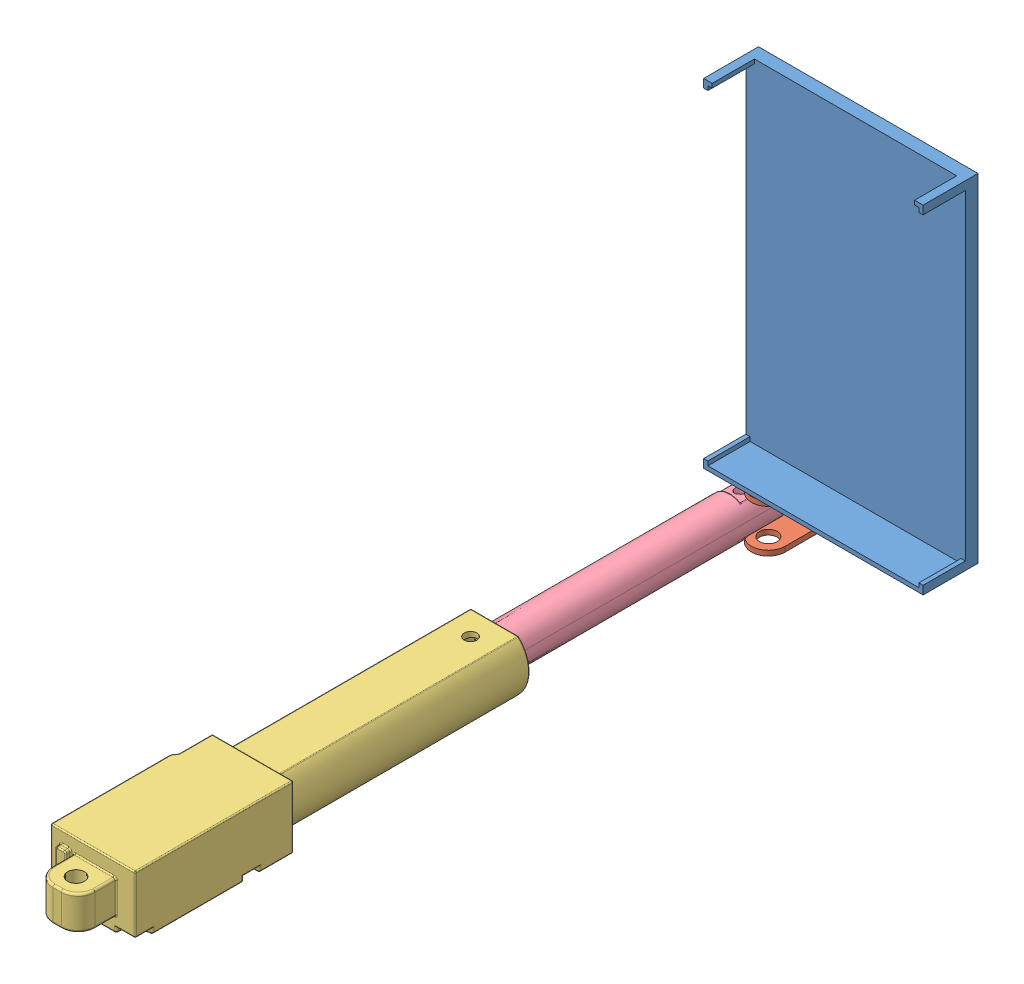
SolidWorks assembly 装配体1, configuration Default. Lengths in mm.
Overall size (55.08 93.4 173.61).
4 component instances, 4 part files, 6 mates.
Components (placement in the parent):
- 底座-1: 底座 [默认] at (19.7151 46.7451 68.604) size (52 80 13)
- 连接件-1: 连接件 [默认] at (4.797 -4.6549 71.653) x (1 0 0) z (0 1 0) size (8 12.95 11.4)
- 伸缩杆1-1: 伸缩杆1 [默认] at (0.6316 0.7451 182.6406) x (0 0 -1) z (0 1 0) size (104.3 20 14.8)
- 伸缩杆2-1: 伸缩杆2 [Défaut] at (0.6316 0.7451 177.6406) x (0 0 -1) z (0.273298 -0.96193 0) size (64.66 9.34 9.34)
Mates (geometry in assembly coordinates):
- 重合1: coincident anti-aligned: plane of 底座-1 through (45.7151 6.7451 65.604) normal (0 -1 0); plane of 连接件-1 through (1.1738 6.7451 65.8876) normal (0 1 0)
- 重合2: coincident anti-aligned: plane of 伸缩杆1-1 through (0.6316 0.7451 134.9135) normal (0 0 -1); plane of 伸缩杆2-1 through (0.6316 0.7451 134.9135) normal (0 0 1)
- 同心1: concentric anti-aligned: cylinder of 伸缩杆1-1 through (0.6316 0.7451 134.9135) axis (0 0 -1) radius 4.8688; cylinder of 伸缩杆2-1 through (0.6316 0.7451 79.2135) axis (0 0 1) radius 4.6688
- 平行4: parallel anti-aligned: plane of 底座-1 through (19.7151 46.7451 68.604) normal (0 0 1); plane of 伸缩杆1-1 through (-9.2676 8.1451 192.7135) normal (0 0 -1)
- 距离1: distance = 0 mm anti-aligned: plane of 底座-1 through (45.7151 6.7451 65.604) normal (0 -1 0); plane of 伸缩杆1-1 through (6.2209 6.7451 134.9135) normal (0 1 0)
- 平行7: parallel aligned: plane of 底座-1 through (45.7151 6.7451 65.604) normal (1 0 0); plane of 伸缩杆1-1 through (10.6316 8.1451 192.7135) normal (1 0 0)
